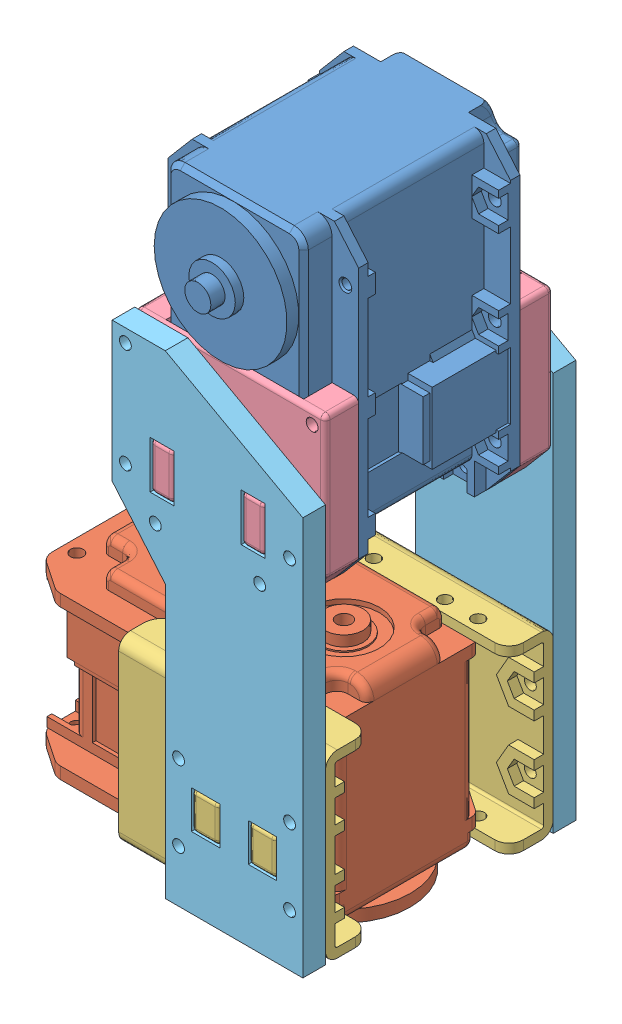
SolidWorks assembly shoulder_pitch_link, configuration Default. Lengths in mm.
Overall size (68.2 208.56 59.56).
8 component instances, 5 part files, 24 mates.
Components (placement in the parent):
- EX-106+-1: EX-106+ [Default] at origin size (40.2 200.67 55.3)
- RX-64-1: RX-64 [Default] at (0 -96.2 0) x (0 0 -1) z (0 -1 0) size (40.2 62.1 50)
- Custom Frame - RX 64 to Delrin Plates Upper-1: Custom Frame - RX 64 to Delrin Plates Upper [Default] at (0 -96.2 24) x (1 0 0) z (0 1 0) size (43.6 14.06 38)
- Custom Frame - RX 64 to Delrin Plates Upper-2: Custom Frame - RX 64 to Delrin Plates Upper [Default] at (0 -96.2 -24) x (1 0 0) z (0 -1 0) size (43.6 14.06 38)
- Custom Frame - EX 106 to Delrin Plates-1: Custom Frame - EX 106 to Delrin Plates [Default] at (0 -32.9 17) x (0 1 0) z (1 0 0) size (35.4 11.76 40.2)
- Custom Frame - EX 106 to Delrin Plates-2: Custom Frame - EX 106 to Delrin Plates [Default] at (0 -32.9 -17) x (0 1 0) z (-1 0 0) size (35.4 11.76 40.2)
- Connection Plate - EX-106+ to RX-64-1: Connection Plate - EX-106+ to RX-64 [Default] at (20.1 -115.2 24) x (0 1 0) z (0 0 1) size (100 40.2 4.76)
- Connection Plate - EX-106+ to RX-64-2: Connection Plate - EX-106+ to RX-64 [Default] at (20.1 -115.2 -28.7625) x (0 1 0) z (0 0 1) size (100 40.2 4.76)
Mates (geometry in assembly coordinates):
- Parallel17: parallel aligned: plane of EX-106+-1 through (-14.5 -45 23) normal (0 0 1); plane of Custom Frame - RX 64 to Delrin Plates Upper-1 through (-16.203 -79.04 24) normal (0 0 1)
- Coincident86: coincident anti-aligned: plane of EX-106+-1 through (-14.5 -45 23) normal (0 0 1); plane of Custom Frame - EX 106 to Delrin Plates-1 through (14.5 -80.2142 23) normal (0 0 -1)
- Coincident87: coincident anti-aligned: plane of EX-106+-1 through (-14.5 -45 23) normal (-1 0 0); plane of Custom Frame - EX 106 to Delrin Plates-1 through (-14.5 -80.2142 23) normal (1 0 0)
- Coincident88: coincident anti-aligned: plane of EX-106+-1 through (14.5 -45 23) normal (0 -1 0); plane of Custom Frame - EX 106 to Delrin Plates-1 through (20.1 -45 24) normal (0 1 0)
- Coincident89: coincident anti-aligned: plane of EX-106+-1 through (-15.8711 14.5 -23) normal (0 0 -1); plane of Custom Frame - EX 106 to Delrin Plates-2 through (-14.5 -80.2142 -23) normal (0 0 1)
- Coincident90: coincident anti-aligned: plane of EX-106+-1 through (-14.5 9.25 -23) normal (-1 0 0); plane of Custom Frame - EX 106 to Delrin Plates-2 through (-14.5 -80.2142 -23) normal (1 0 0)
- Coincident91: coincident anti-aligned: plane of EX-106+-1 through (-9.25 -45 -21) normal (0 -1 0); plane of Custom Frame - EX 106 to Delrin Plates-2 through (-20.1 -45 -24) normal (0 1 0)
- Coincident82: coincident anti-aligned: plane of RX-64-1 through (-49.322 -79.2 20.904) normal (0 1 0); plane of Custom Frame - RX 64 to Delrin Plates Upper-1 through (-22.22 -79.2 14.564) normal (0 -1 0)
- Concentric50: concentric aligned: cylinder of RX-64-1 through (4 -81.7 17.3) axis (0 1 0) radius 1.35; cylinder of Custom Frame - RX 64 to Delrin Plates Upper-1 through (4 -77.2 17.3) axis (0 1 0) radius 1.3
- Concentric51: concentric aligned: cylinder of RX-64-1 through (-18 -81.7 17.3) axis (0 1 0) radius 1.35; cylinder of Custom Frame - RX 64 to Delrin Plates Upper-1 through (-18 -77.2 17.3) axis (0 1 0) radius 1.3
- Coincident83: coincident anti-aligned: plane of RX-64-1 through (-49.322 -79.2 20.904) normal (0 1 0); plane of Custom Frame - RX 64 to Delrin Plates Upper-2 through (-22.22 -79.2 -21.636) normal (0 -1 0)
- Concentric52: concentric aligned: cylinder of RX-64-1 through (-18 -81.7 -17.3) axis (0 1 0) radius 1.35; cylinder of Custom Frame - RX 64 to Delrin Plates Upper-2 through (-18 -77.2 -17.3) axis (0 1 0) radius 1.3
- Concentric53: concentric aligned: cylinder of RX-64-1 through (4 -81.7 -17.3) axis (0 1 0) radius 1.35; cylinder of Custom Frame - RX 64 to Delrin Plates Upper-2 through (4 -77.2 -17.3) axis (0 1 0) radius 1.3
- Coincident92: coincident aligned: plane of Custom Frame - RX 64 to Delrin Plates Upper-1 through (-16.203 -79.04 24) normal (0 0 1); plane of Custom Frame - EX 106 to Delrin Plates-1 through (-20.1 -15.2 24) normal (0 0 1)
- Parallel18: parallel aligned: plane of Custom Frame - EX 106 to Delrin Plates-1 through (-20.1 -50.6 24) normal (-1 0 0); plane of Custom Frame - RX 64 to Delrin Plates Upper-1 through (-23.5 -79.7 21.5) normal (-1 0 0)
- Coincident109: coincident aligned: plane of Custom Frame - RX 64 to Delrin Plates Upper-1 through (-22.22 -115.2 21.636) normal (0 -1 0); plane of Connection Plate - EX-106+ to RX-64-1 through (-8.9 -115.2 28.7625) normal (0 -1 0)
- Parallel28: parallel aligned: plane of Custom Frame - RX 64 to Delrin Plates Upper-2 through (20.1 -112.7 -21.5) normal (1 0 0); plane of Custom Frame - EX 106 to Delrin Plates-2 through (20.1 -50.6 -24) normal (1 0 0)
- Coincident119: coincident anti-aligned: plane of Custom Frame - RX 64 to Delrin Plates Upper-2 through (14.6 -92.2 -28.7625) normal (1 0 0); plane of Connection Plate - EX-106+ to RX-64-2 through (14.6 -100.2 -28.7625) normal (-1 0 0)
- Coincident103: coincident aligned: plane of Custom Frame - EX 106 to Delrin Plates-1 through (-20.1 -50.6 24) normal (-1 0 0); plane of Connection Plate - EX-106+ to RX-64-1 through (-20.1 -44.6 28.7625) normal (-1 0 0)
- Coincident104: coincident anti-aligned: plane of Custom Frame - EX 106 to Delrin Plates-1 through (-20.1 -15.2 24) normal (0 0 1); plane of Connection Plate - EX-106+ to RX-64-1 through (20.1 -115.2 24) normal (0 0 -1)
- Coincident105: coincident aligned: plane of Custom Frame - EX 106 to Delrin Plates-1 through (20.1 -15.2 24) normal (0 1 0); plane of Connection Plate - EX-106+ to RX-64-1 through (-20.1 -15.2 28.7625) normal (0 1 0)
- Coincident106: coincident anti-aligned: plane of Custom Frame - EX 106 to Delrin Plates-2 through (20.1 -15.2 -24) normal (0 0 -1); plane of Connection Plate - EX-106+ to RX-64-2 through (20.1 -115.2 -24) normal (0 0 1)
- Coincident107: coincident aligned: plane of Custom Frame - EX 106 to Delrin Plates-2 through (-20.1 -15.2 -24) normal (0 1 0); plane of Connection Plate - EX-106+ to RX-64-2 through (-20.1 -15.2 -24) normal (0 1 0)
- Coincident108: coincident aligned: plane of Custom Frame - EX 106 to Delrin Plates-2 through (-20.1 -50.6 -24) normal (-1 0 0); plane of Connection Plate - EX-106+ to RX-64-2 through (-20.1 -44.6 -24) normal (-1 0 0)
